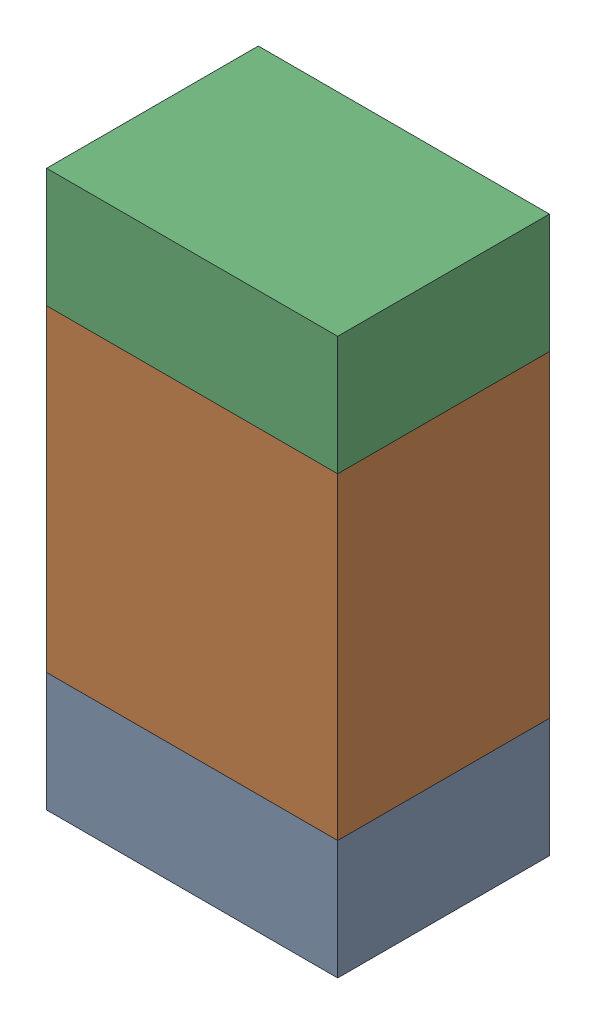
SolidWorks assembly R703PCB, configuration Default. Lengths in mm.
Overall size (0.55 1.05 0.4).
6 component instances, 2 part files, 0 mates.
Components (placement in the parent):
- 846483288-1: 846483288 [Default] at (116.8001 123.2876 -2.0638) size (0.55 0.22 0.4)
  - Extruded_12-1: Extruded_12 [Default] at origin size (0.55 0.22 0.4)
- 846483424-1: 846483424 [Default] at (116.8001 123.7001 -2.0638) size (0.55 0.6 0.4)
  - Extruded_13-1: Extruded_13 [Default] at origin size (0.55 0.6 0.4)
- 846483288-2: 846483288 [Default] at (116.8001 124.1126 -2.0638) size (0.55 0.22 0.4)
  - Extruded_12-1: Extruded_12 [Default] at origin size (0.55 0.22 0.4)
